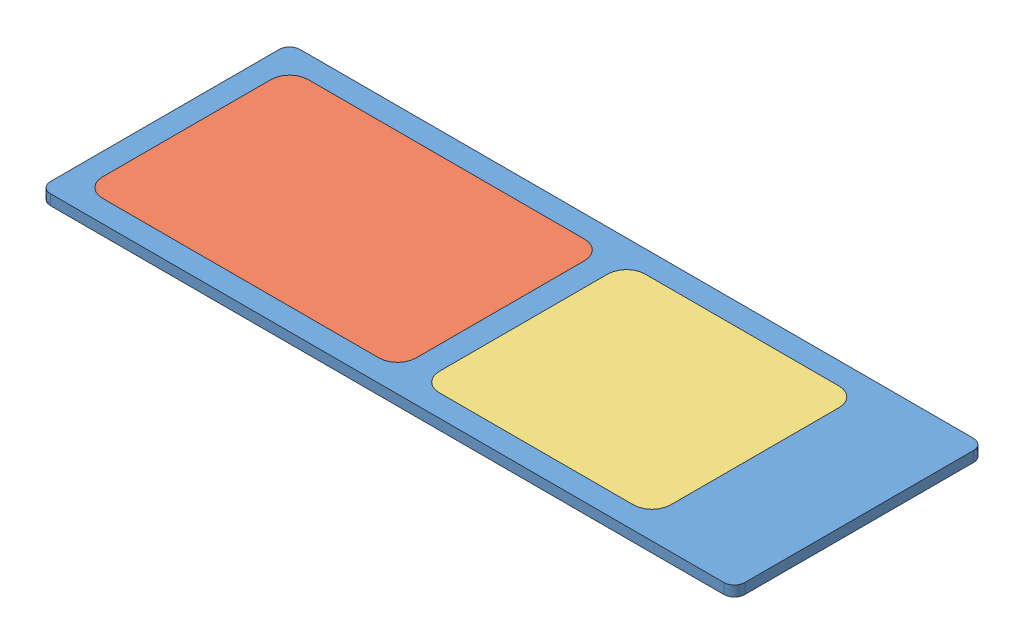
SolidWorks assembly bottom_lid_assembly, configuration Default. Lengths in mm.
Overall size (599 9 215.4).
3 component instances, 3 part files, 6 mates.
Components (placement in the parent):
- lid_rectangular_bottom-1: lid_rectangular_bottom [Default] at (25.7039 60.1265 -261.3321) x (1 0 0) z (0 -1 0) size (599 215.4 9)
- Lid_window-5: Lid_window [Default] at (-254.7961 60.1265 -261.3321) x (1 0 0) z (0 -1 0) size (225.62 177.4 6)
- lid_window_bottom_small-1: lid_window_bottom_small [Default] at (25.7039 54.1265 -261.3321) x (-1 0 0) z (0 1 0) size (169.5 177.4 6)
Mates (geometry in assembly coordinates):
- Coincident5: coincident anti-aligned: plane of lid_rectangular-1 through (-238.7961 54.1265 -235.3321) normal (0 1 0); plane of Lid_window-5 through (-20.4461 54.1265 -235.3321) normal (0 -1 0)
- Concentric1: concentric: cylinder of lid_rectangular-1 through (-238.7961 54.1265 -89.9321) axis (0 1 0) radius 16; cylinder of Lid_window-5 through (-238.7961 54.1265 -89.9321) axis (0 1 0) radius 16
- InPlace1: in place: plane of lid_rectangular_bottom-1 through (219.2039 54.1265 -235.3321) normal (0 1 0); plane of ? through (0 54.1265 0) normal (0 1 0); moOrthogonalPlaneRef_w of lid_rectangular_bottom-1 through (219.2039 54.1265 -235.3321) normal (0 1 0); plane of ? through (0 54.1265 0) normal (0 0 -1); plane of lid_rectangular_bottom-1 through (219.2039 54.1265 -235.3321) normal (0 1 0); plane of ? through (0 54.1265 0) normal (1 0 0); plane of lid_rectangular_bottom-1 through (189.2039 54.1265 -235.3321) normal (0 1 0); unknown of lid_window_bottom_small-1
- Coincident6: coincident aligned: plane of ?; plane of ?
- Coincident7: coincident aligned: moOrthogonalPlaneRef_w of lid_rectangular_bottom-1 through (25.7039 54.1265 -261.3321) normal (0 0 1); plane of Part1^bottom_lid_assembly-1 through (25.7039 54.1265 -261.3321) normal (0 0 1)
- Coincident8: coincident anti-aligned: moOrthogonalPlaneRef_w of lid_rectangular_bottom-1 through (25.7039 54.1265 -261.3321) normal (1 0 0); plane of Part1^bottom_lid_assembly-1 through (25.7039 54.1265 -261.3321) normal (-1 0 0)
